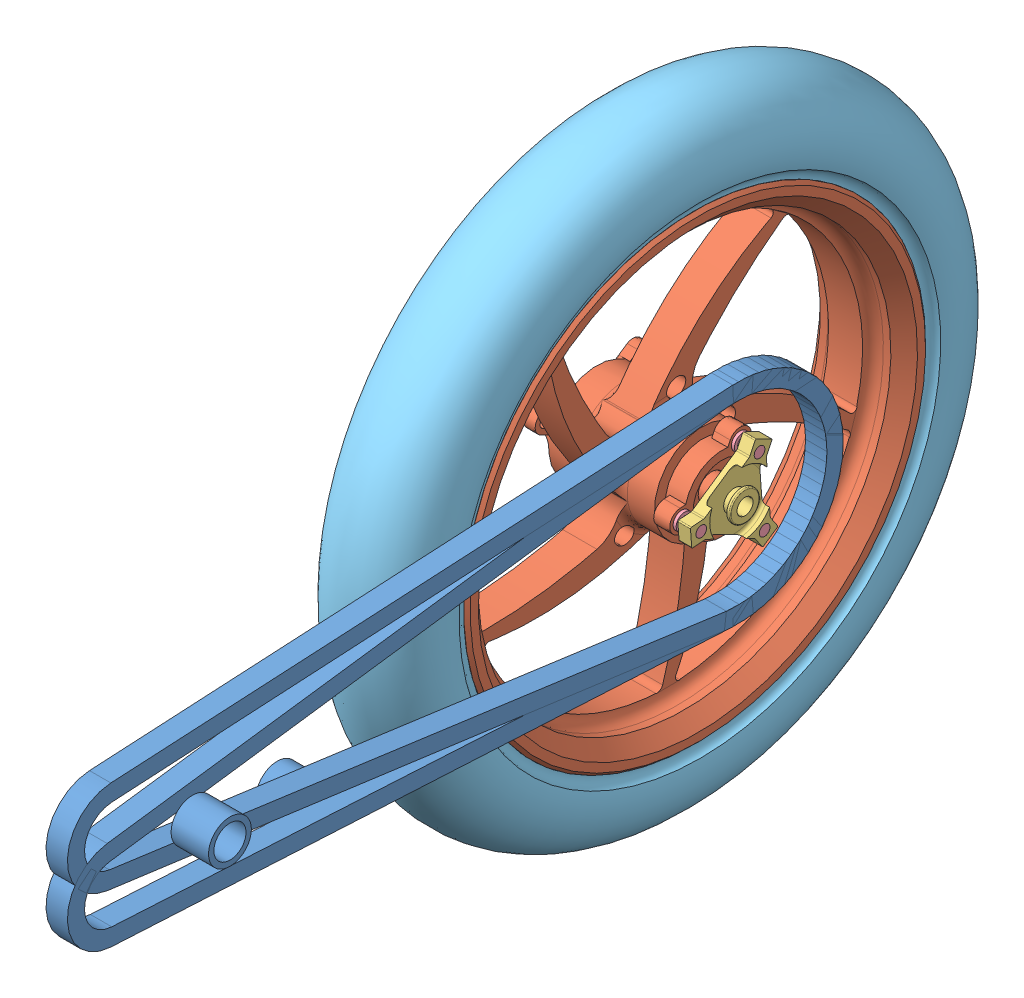
SolidWorks assembly Złożenie1, configuration Domyślna. Lengths in mm.
Overall size (240 650.46 952.51).
9 component instances, 5 part files, 8 mates.
Components (placement in the parent):
- ver_3.1-2: ver_3.1 [Domyślna] at origin size (240 196 725.28)
- REAR WHEEL WITH SPROCKET CARRIER ASSEMBLY-2: REAR WHEEL WITH SPROCKET CARRIER ASSEMBLY [Domyślna] at (-0.7843 -431.0075 -538.6394) x (0 0.072267 -0.997385) z (0 0.997385 0.072267) size (431.81 154.74 431.81)
  - 04-RW-001-002 nowa-1: 04-RW-001-002 nowa [Domyślna] at (4.578 -1.1734 431.8057) size (431.81 133.42 431.81)
  - sprocket assembly-1: sprocket assembly [Domyślna] at (-0.5508 -165.5721 430.6155) x (0 0 -1) z (0 1 0) size (90.32 78.58 29.82)
    - sprocket carrier-1: sprocket carrier [Domyślna] at (-1.1903 -5.1288 75.3221) size (90.32 78.49 29.82)
    - sprocket carrier connect part-1: sprocket carrier connect part [Domyślna] at (-1.1903 32.8712 103.7721) x (-0.972548 0.232702 0) z (0 0 -1) size (16 16 25.45)
    - sprocket carrier connect part-2: sprocket carrier connect part [Domyślna] at (-34.0992 -24.1288 103.7721) x (-0.975807 -0.218636 0) z (0 0 -1) size (16 16 25.45)
    - sprocket carrier connect part-3: sprocket carrier connect part [Domyślna] at (31.7187 -24.1288 103.7721) x (-0.734897 -0.678179 0) z (0 0 -1) size (16 16 25.45)
- 04-FW-001-001-Front Tire-1: 04-FW-001-001-Front Tire [Domyślna] at (-1.2304 0 -512) x (0 -0.990296 0.138977) z (0 0.138977 0.990296) size (576 100.38 576)
Mates (geometry in assembly coordinates):
- Wspólnie5: coincident: plane of ver_3.1-2 through (0 0 0) normal (0 0 1); plane of assembly through (0 0 0) normal (0 0 1)
- Wspólnie6: coincident: plane of ver_3.1-2 through (0 0 0) normal (0 1 0); plane of assembly through (0 0 0) normal (0 1 0)
- Wspólnie7: coincident: plane of ver_3.1-2 through (0 0 0) normal (1 0 0); plane of assembly through (0 0 0) normal (1 0 0)
- Koncentryczne3: concentric: line of ver_3.1-2 through (-75 0 -512) axis (1 0 0); cylinder of REAR WHEEL WITH SPROCKET CARRIER ASSEMBLY-2/sprocket assembly-1/sprocket carrier-1 through (59.4657 0 -512) axis (1 0 0) radius 7.5
- Wspólnie8: coincident: line of REAR WHEEL WITH SPROCKET CARRIER ASSEMBLY-2 through (0 -201.0343 -490.9031) axis (0 0.072267 -0.997385); plane of assembly
- Koncentryczne4: concentric: line of ver_3.1-2 through (-75 0 -512) axis (1 0 0); cylinder of REAR WHEEL WITH SPROCKET CARRIER ASSEMBLY-2/sprocket assembly-1/sprocket carrier-1 through (59.4657 0 -512) axis (1 0 0) radius 7.5
- Koncentryczne5: concentric: cylinder of REAR WHEEL WITH SPROCKET CARRIER ASSEMBLY-2/sprocket assembly-1/sprocket carrier-1 through (59.4657 0 -512) axis (1 0 0) radius 7.5; circle of 04-FW-001-001-Front Tire-1
- Zablokuj1: lock: unknown of REAR WHEEL WITH SPROCKET CARRIER ASSEMBLY-2/04-RW-001-002 nowa-1; unknown of 04-FW-001-001-Front Tire-1
